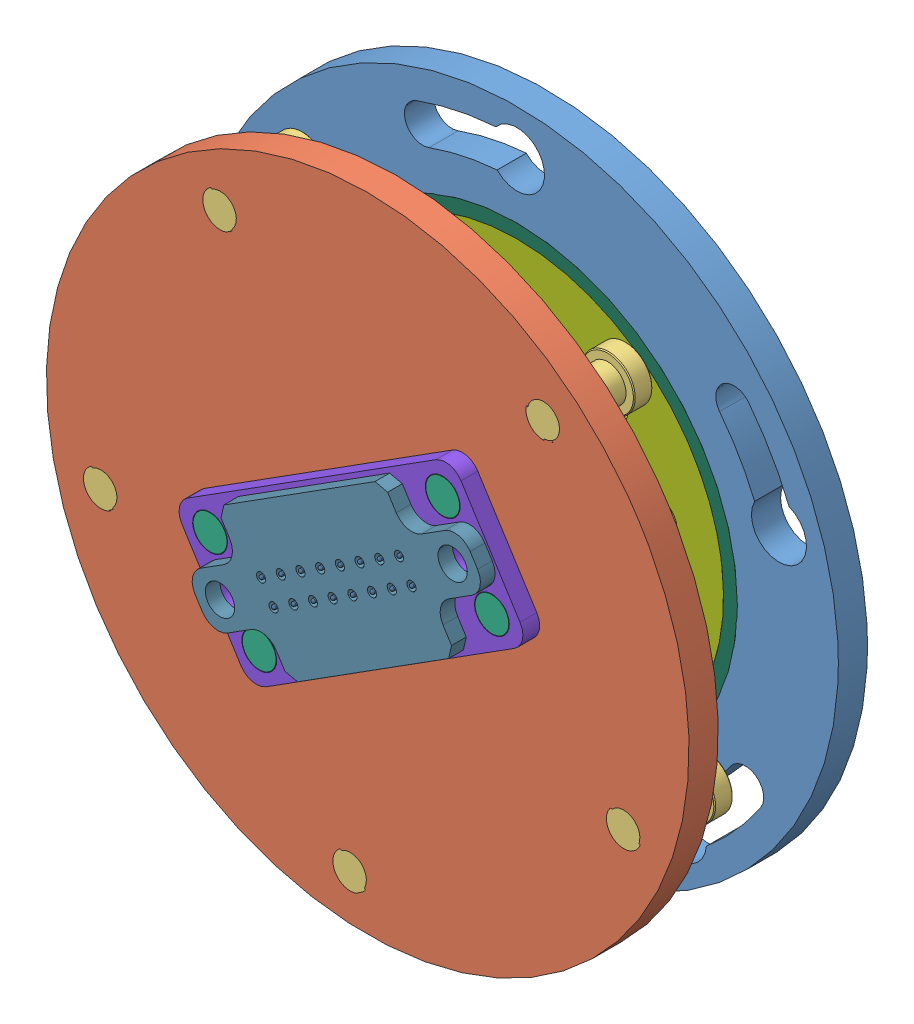
SolidWorks assembly Star_Twist_Lock, configuration Default. Lengths in mm.
Overall size (138 138 26.18).
100 component instances, 15 part files, 39 mates.
Components (placement in the parent):
- Star_Twist_Lock_Female_Plate-1: Star_Twist_Lock_Female_Plate [Default] at (10.9532 52.4325 90.508) size (100 100 3.17)
- Star_Twist_Lock_Male_Plate-1: Star_Twist_Lock_Male_Plate [Default] at (10.9532 52.4325 106.7596) x (0.844579 0.535431 0) z (0 0 1) size (100 100 3.17)
- dowel_shelf_pin-1: dowel_shelf_pin [Default] at (-5.1097 77.7699 109.9346) x (1 0 0) z (0 1 0) size (5.8 9 5.8)
- dowel_shelf_pin-4: dowel_shelf_pin [Default] at (30.0868 75.5389 109.9346) x (1 0 0) z (0 1 0) size (5.8 9 5.8)
- dowel_shelf_pin-5: dowel_shelf_pin [Default] at (38.8414 41.3757 109.9346) x (1 0 0) z (0 1 0) size (5.8 9 5.8)
- dowel_shelf_pin-6: dowel_shelf_pin [Default] at (9.0555 22.4926 109.9346) x (1 0 0) z (0 1 0) size (5.8 9 5.8)
- dowel_shelf_pin-7: dowel_shelf_pin [Default] at (-18.1077 44.9854 109.9346) x (1 0 0) z (0 1 0) size (5.8 9 5.8)
- mill-max-419-10-216-00-001000-1: mill-max-419-10-216-00-001000 [MillMaxsldprt2014419-XX-XXX-00-0010001610uGoldoverNickelPage14off] at (3.9904 45.0109 94.699) x (0.844579 0.535431 0) z (0.535431 -0.844579 0) size (20.32 7.37 5.08)
  - mill-max-419-10-216-00-001000_P4XX-21-010-00-000000-1: mill-max-419-10-216-00-001000_P4XX-21-010-00-000000 [P416-21-010-00-000000] at origin size (20.32 2.79 5.08)
  - mill-max-419-10-216-00-001000_1942-1: mill-max-419-10-216-00-001000_1942 [Default] at (0.9644 0 -1.27) x (0 -1 0) z (0 0 1) size (7.37 1.78 1.78)
  - mill-max-419-10-216-00-001000_1942-35: mill-max-419-10-216-00-001000_1942 [Default] at (0.9644 0 -3.81) x (0 -1 0) z (0 0 1) size (7.37 1.78 1.78)
  - mill-max-419-10-216-00-001000_1942-36: mill-max-419-10-216-00-001000_1942 [Default] at (3.5044 0 -3.81) x (0 -1 0) z (0 0 1) size (7.37 1.78 1.78)
  - mill-max-419-10-216-00-001000_1942-20: mill-max-419-10-216-00-001000_1942 [Default] at (3.5044 0 -1.27) x (0 -1 0) z (0 0 1) size (7.37 1.78 1.78)
  - mill-max-419-10-216-00-001000_1942-37: mill-max-419-10-216-00-001000_1942 [Default] at (6.0444 0 -3.81) x (0 -1 0) z (0 0 1) size (7.37 1.78 1.78)
  - mill-max-419-10-216-00-001000_1942-38: mill-max-419-10-216-00-001000_1942 [Default] at (8.5844 0 -3.81) x (0 -1 0) z (0 0 1) size (7.37 1.78 1.78)
  - mill-max-419-10-216-00-001000_1942-39: mill-max-419-10-216-00-001000_1942 [Default] at (11.1244 0 -3.81) x (0 -1 0) z (0 0 1) size (7.37 1.78 1.78)
  - mill-max-419-10-216-00-001000_1942-40: mill-max-419-10-216-00-001000_1942 [Default] at (13.6644 0 -3.81) x (0 -1 0) z (0 0 1) size (7.37 1.78 1.78)
  - mill-max-419-10-216-00-001000_1942-41: mill-max-419-10-216-00-001000_1942 [Default] at (16.2044 0 -3.81) x (0 -1 0) z (0 0 1) size (7.37 1.78 1.78)
  - mill-max-419-10-216-00-001000_1942-42: mill-max-419-10-216-00-001000_1942 [Default] at (18.7444 0 -3.81) x (0 -1 0) z (0 0 1) size (7.37 1.78 1.78)
  - mill-max-419-10-216-00-001000_1942-29: mill-max-419-10-216-00-001000_1942 [Default] at (6.0444 0 -1.27) x (0 -1 0) z (0 0 1) size (7.37 1.78 1.78)
  - mill-max-419-10-216-00-001000_1942-30: mill-max-419-10-216-00-001000_1942 [Default] at (8.5844 0 -1.27) x (0 -1 0) z (0 0 1) size (7.37 1.78 1.78)
  - mill-max-419-10-216-00-001000_1942-31: mill-max-419-10-216-00-001000_1942 [Default] at (11.1244 0 -1.27) x (0 -1 0) z (0 0 1) size (7.37 1.78 1.78)
  - mill-max-419-10-216-00-001000_1942-32: mill-max-419-10-216-00-001000_1942 [Default] at (13.6644 0 -1.27) x (0 -1 0) z (0 0 1) size (7.37 1.78 1.78)
  - mill-max-419-10-216-00-001000_1942-33: mill-max-419-10-216-00-001000_1942 [Default] at (16.2044 0 -1.27) x (0 -1 0) z (0 0 1) size (7.37 1.78 1.78)
  - mill-max-419-10-216-00-001000_1942-34: mill-max-419-10-216-00-001000_1942 [Default] at (18.7444 0 -1.27) x (0 -1 0) z (0 0 1) size (7.37 1.78 1.78)
- Dowel_Pin_93600A133-11: Dowel_Pin_93600A133 [93600A133] at (0.9617 40.1781 103.1596) x (0 0 1) z (-1 0 0) size (17.2 4 4)
- Pogo_Fixture_Female_Front_Plate-1: Pogo_Fixture_Female_Front_Plate [Default] at (10.9532 52.4325 93.683) x (0.844579 0.535431 0) z (0 0 -1) size (100 100 3.17)
- Pogo_Fixture_Male_Front_Plate-2: Pogo_Fixture_Male_Front_Plate [Default] at (10.9532 52.4325 106.7596) x (0.844579 0.535431 0) z (0 0 1) size (36 16 5)
- Dowel_Pin_93600A133-8: Dowel_Pin_93600A133 [93600A133] at (-4.3926 48.6239 103.1596) x (0 0 1) z (-1 0 0) size (17.2 4 4)
- Dowel_Pin_93600A133-9: Dowel_Pin_93600A133 [93600A133] at (20.9448 64.6869 103.1596) x (0 0 1) z (-1 0 0) size (17.2 4 4)
- Dowel_Pin_93600A133-10: Dowel_Pin_93600A133 [93600A133] at (26.2991 56.2411 103.1596) x (0 0 1) z (-1 0 0) size (17.2 4 4)
- mill-max-823-22-016-10-004101-1: mill-max-823-22-016-10-004101 [Default] at (1.2705 49.3014 108.5592) x (0.844579 0.535431 0) z (-0.535431 0.844579 0) size (20.32 7.75 5.08)
  - mill-max-823-22-016-10-004101_P4XX-28-010-00-090000-1: mill-max-823-22-016-10-004101_P4XX-28-010-00-090000 [Default] at origin size (20.32 2.79 5.08)
  - mill-max-823-22-016-10-004101_0963-0-1: mill-max-823-22-016-10-004101_0963-0 [Default] at (0.9644 -4.953 -1.27) x (0 1 0) z (0 0 1) size (4.04 1.31 1.31)
  - mill-max-823-22-016-10-004101_0953-X-1: mill-max-823-22-016-10-004101_0953-X [Default] at (0.9644 -3.2004 -1.27) x (0 1 0) z (-0.980895 0 0.194537) size (2.69 1.83 1.83)
  - mill-max-823-22-016-10-004101_0918-X-1: mill-max-823-22-016-10-004101_0918-X [Default] at (0.9644 -1.1938 -1.27) x (0 1 0) z (0 0 1) size (3.99 1.25 1.25)
  - mill-max-823-22-016-10-004101_6875-0-00-00-75-XX-43-0C-1: mill-max-823-22-016-10-004101_6875-0-00-00-75-XX-43-0C [Default] at (0.9644 0.6557 -1.27) x (-0.956034 0 -0.293257) z (0 -1 0) size (0.2 0.07 3.45)
  - mill-max-823-22-016-10-004101_0963-0-2: mill-max-823-22-016-10-004101_0963-0 [Default] at (0.9644 -4.953 -3.81) x (0 1 0) z (0 0 1) size (4.04 1.31 1.31)
  - mill-max-823-22-016-10-004101_0953-X-2: mill-max-823-22-016-10-004101_0953-X [Default] at (0.9644 -3.2004 -3.81) x (0 1 0) z (0 0 1) size (2.69 1.83 1.83)
  - mill-max-823-22-016-10-004101_0918-X-2: mill-max-823-22-016-10-004101_0918-X [Default] at (0.9644 -1.1938 -3.81) x (0 1 0) z (0.012366 0 0.999924) size (3.99 1.25 1.25)
  - mill-max-823-22-016-10-004101_6875-0-00-00-75-XX-43-0C-2: mill-max-823-22-016-10-004101_6875-0-00-00-75-XX-43-0C [Default] at (0.9644 -2.5164 -3.81) x (-0.692815 0 0.721116) z (0 1 0) size (0.2 0.07 3.45)
  - mill-max-823-22-016-10-004101_6875-0-00-00-75-XX-43-0C-3: mill-max-823-22-016-10-004101_6875-0-00-00-75-XX-43-0C [Default] at (3.5044 -2.5164 -3.81) x (-0.692815 0 0.721116) z (0 1 0) size (0.2 0.07 3.45)
  - mill-max-823-22-016-10-004101_0918-X-3: mill-max-823-22-016-10-004101_0918-X [Default] at (3.5044 -1.1938 -3.81) x (0 1 0) z (0.012366 0 0.999924) size (3.99 1.25 1.25)
  - mill-max-823-22-016-10-004101_0953-X-3: mill-max-823-22-016-10-004101_0953-X [Default] at (3.5044 -3.2004 -3.81) x (0 1 0) z (0 0 1) size (2.69 1.83 1.83)
  - mill-max-823-22-016-10-004101_0963-0-3: mill-max-823-22-016-10-004101_0963-0 [Default] at (3.5044 -4.953 -3.81) x (0 1 0) z (0 0 1) size (4.04 1.31 1.31)
  - mill-max-823-22-016-10-004101_6875-0-00-00-75-XX-43-0C-4: mill-max-823-22-016-10-004101_6875-0-00-00-75-XX-43-0C [Default] at (3.5044 0.6557 -1.27) x (-0.956034 0 -0.293257) z (0 -1 0) size (0.2 0.07 3.45)
  - mill-max-823-22-016-10-004101_0918-X-4: mill-max-823-22-016-10-004101_0918-X [Default] at (3.5044 -1.1938 -1.27) x (0 1 0) z (0 0 1) size (3.99 1.25 1.25)
  - mill-max-823-22-016-10-004101_0953-X-4: mill-max-823-22-016-10-004101_0953-X [Default] at (3.5044 -3.2004 -1.27) x (0 1 0) z (-0.980895 0 0.194537) size (2.69 1.83 1.83)
  - mill-max-823-22-016-10-004101_0963-0-4: mill-max-823-22-016-10-004101_0963-0 [Default] at (3.5044 -4.953 -1.27) x (0 1 0) z (0 0 1) size (4.04 1.31 1.31)
  - mill-max-823-22-016-10-004101_6875-0-00-00-75-XX-43-0C-5: mill-max-823-22-016-10-004101_6875-0-00-00-75-XX-43-0C [Default] at (6.0444 -2.5164 -3.81) x (-0.692815 0 0.721116) z (0 1 0) size (0.2 0.07 3.45)
  - mill-max-823-22-016-10-004101_6875-0-00-00-75-XX-43-0C-6: mill-max-823-22-016-10-004101_6875-0-00-00-75-XX-43-0C [Default] at (8.5844 -2.5164 -3.81) x (-0.692815 0 0.721116) z (0 1 0) size (0.2 0.07 3.45)
  - mill-max-823-22-016-10-004101_6875-0-00-00-75-XX-43-0C-7: mill-max-823-22-016-10-004101_6875-0-00-00-75-XX-43-0C [Default] at (11.1244 -2.5164 -3.81) x (-0.692815 0 0.721116) z (0 1 0) size (0.2 0.07 3.45)
  - mill-max-823-22-016-10-004101_6875-0-00-00-75-XX-43-0C-8: mill-max-823-22-016-10-004101_6875-0-00-00-75-XX-43-0C [Default] at (13.6644 -2.5164 -3.81) x (-0.692815 0 0.721116) z (0 1 0) size (0.2 0.07 3.45)
  - mill-max-823-22-016-10-004101_6875-0-00-00-75-XX-43-0C-9: mill-max-823-22-016-10-004101_6875-0-00-00-75-XX-43-0C [Default] at (16.2044 -2.5164 -3.81) x (-0.692815 0 0.721116) z (0 1 0) size (0.2 0.07 3.45)
  - mill-max-823-22-016-10-004101_6875-0-00-00-75-XX-43-0C-10: mill-max-823-22-016-10-004101_6875-0-00-00-75-XX-43-0C [Default] at (18.7444 -2.5164 -3.81) x (-0.692815 0 0.721116) z (0 1 0) size (0.2 0.07 3.45)
  - mill-max-823-22-016-10-004101_0918-X-5: mill-max-823-22-016-10-004101_0918-X [Default] at (6.0444 -1.1938 -3.81) x (0 1 0) z (0.012366 0 0.999924) size (3.99 1.25 1.25)
  - mill-max-823-22-016-10-004101_0918-X-6: mill-max-823-22-016-10-004101_0918-X [Default] at (8.5844 -1.1938 -3.81) x (0 1 0) z (0.012366 0 0.999924) size (3.99 1.25 1.25)
  - mill-max-823-22-016-10-004101_0918-X-7: mill-max-823-22-016-10-004101_0918-X [Default] at (11.1244 -1.1938 -3.81) x (0 1 0) z (0.012366 0 0.999924) size (3.99 1.25 1.25)
  - mill-max-823-22-016-10-004101_0918-X-8: mill-max-823-22-016-10-004101_0918-X [Default] at (13.6644 -1.1938 -3.81) x (0 1 0) z (0.012366 0 0.999924) size (3.99 1.25 1.25)
  - mill-max-823-22-016-10-004101_0918-X-9: mill-max-823-22-016-10-004101_0918-X [Default] at (16.2044 -1.1938 -3.81) x (0 1 0) z (0.012366 0 0.999924) size (3.99 1.25 1.25)
  - mill-max-823-22-016-10-004101_0918-X-10: mill-max-823-22-016-10-004101_0918-X [Default] at (18.7444 -1.1938 -3.81) x (0 1 0) z (0.012366 0 0.999924) size (3.99 1.25 1.25)
  - mill-max-823-22-016-10-004101_0953-X-5: mill-max-823-22-016-10-004101_0953-X [Default] at (6.0444 -3.2004 -3.81) x (0 1 0) z (0 0 1) size (2.69 1.83 1.83)
  - mill-max-823-22-016-10-004101_0953-X-6: mill-max-823-22-016-10-004101_0953-X [Default] at (8.5844 -3.2004 -3.81) x (0 1 0) z (0 0 1) size (2.69 1.83 1.83)
  - mill-max-823-22-016-10-004101_0953-X-7: mill-max-823-22-016-10-004101_0953-X [Default] at (11.1244 -3.2004 -3.81) x (0 1 0) z (0 0 1) size (2.69 1.83 1.83)
  - mill-max-823-22-016-10-004101_0953-X-8: mill-max-823-22-016-10-004101_0953-X [Default] at (13.6644 -3.2004 -3.81) x (0 1 0) z (0 0 1) size (2.69 1.83 1.83)
  - mill-max-823-22-016-10-004101_0953-X-9: mill-max-823-22-016-10-004101_0953-X [Default] at (16.2044 -3.2004 -3.81) x (0 1 0) z (0 0 1) size (2.69 1.83 1.83)
  - mill-max-823-22-016-10-004101_0953-X-10: mill-max-823-22-016-10-004101_0953-X [Default] at (18.7444 -3.2004 -3.81) x (0 1 0) z (0 0 1) size (2.69 1.83 1.83)
  - mill-max-823-22-016-10-004101_0963-0-5: mill-max-823-22-016-10-004101_0963-0 [Default] at (6.0444 -4.953 -3.81) x (0 1 0) z (0 0 1) size (4.04 1.31 1.31)
  - mill-max-823-22-016-10-004101_0963-0-6: mill-max-823-22-016-10-004101_0963-0 [Default] at (8.5844 -4.953 -3.81) x (0 1 0) z (0 0 1) size (4.04 1.31 1.31)
  - mill-max-823-22-016-10-004101_0963-0-7: mill-max-823-22-016-10-004101_0963-0 [Default] at (11.1244 -4.953 -3.81) x (0 1 0) z (0 0 1) size (4.04 1.31 1.31)
  - mill-max-823-22-016-10-004101_0963-0-8: mill-max-823-22-016-10-004101_0963-0 [Default] at (13.6644 -4.953 -3.81) x (0 1 0) z (0 0 1) size (4.04 1.31 1.31)
  - mill-max-823-22-016-10-004101_0963-0-9: mill-max-823-22-016-10-004101_0963-0 [Default] at (16.2044 -4.953 -3.81) x (0 1 0) z (0 0 1) size (4.04 1.31 1.31)
  - mill-max-823-22-016-10-004101_0963-0-10: mill-max-823-22-016-10-004101_0963-0 [Default] at (18.7444 -4.953 -3.81) x (0 1 0) z (0 0 1) size (4.04 1.31 1.31)
  - mill-max-823-22-016-10-004101_6875-0-00-00-75-XX-43-0C-11: mill-max-823-22-016-10-004101_6875-0-00-00-75-XX-43-0C [Default] at (6.0444 0.6557 -1.27) x (-0.956034 0 -0.293257) z (0 -1 0) size (0.2 0.07 3.45)
  - mill-max-823-22-016-10-004101_6875-0-00-00-75-XX-43-0C-12: mill-max-823-22-016-10-004101_6875-0-00-00-75-XX-43-0C [Default] at (8.5844 0.6557 -1.27) x (-0.956034 0 -0.293257) z (0 -1 0) size (0.2 0.07 3.45)
  - mill-max-823-22-016-10-004101_6875-0-00-00-75-XX-43-0C-13: mill-max-823-22-016-10-004101_6875-0-00-00-75-XX-43-0C [Default] at (11.1244 0.6557 -1.27) x (-0.956034 0 -0.293257) z (0 -1 0) size (0.2 0.07 3.45)
  - mill-max-823-22-016-10-004101_6875-0-00-00-75-XX-43-0C-14: mill-max-823-22-016-10-004101_6875-0-00-00-75-XX-43-0C [Default] at (13.6644 0.6557 -1.27) x (-0.956034 0 -0.293257) z (0 -1 0) size (0.2 0.07 3.45)
  - mill-max-823-22-016-10-004101_6875-0-00-00-75-XX-43-0C-15: mill-max-823-22-016-10-004101_6875-0-00-00-75-XX-43-0C [Default] at (16.2044 0.6557 -1.27) x (-0.956034 0 -0.293257) z (0 -1 0) size (0.2 0.07 3.45)
  - mill-max-823-22-016-10-004101_6875-0-00-00-75-XX-43-0C-16: mill-max-823-22-016-10-004101_6875-0-00-00-75-XX-43-0C [Default] at (18.7444 0.6557 -1.27) x (-0.956034 0 -0.293257) z (0 -1 0) size (0.2 0.07 3.45)
  - mill-max-823-22-016-10-004101_0918-X-11: mill-max-823-22-016-10-004101_0918-X [Default] at (6.0444 -1.1938 -1.27) x (0 1 0) z (0 0 1) size (3.99 1.25 1.25)
  - mill-max-823-22-016-10-004101_0918-X-12: mill-max-823-22-016-10-004101_0918-X [Default] at (8.5844 -1.1938 -1.27) x (0 1 0) z (0 0 1) size (3.99 1.25 1.25)
  - mill-max-823-22-016-10-004101_0918-X-13: mill-max-823-22-016-10-004101_0918-X [Default] at (11.1244 -1.1938 -1.27) x (0 1 0) z (0 0 1) size (3.99 1.25 1.25)
  - mill-max-823-22-016-10-004101_0918-X-14: mill-max-823-22-016-10-004101_0918-X [Default] at (13.6644 -1.1938 -1.27) x (0 1 0) z (0 0 1) size (3.99 1.25 1.25)
  - mill-max-823-22-016-10-004101_0918-X-15: mill-max-823-22-016-10-004101_0918-X [Default] at (16.2044 -1.1938 -1.27) x (0 1 0) z (0 0 1) size (3.99 1.25 1.25)
  - mill-max-823-22-016-10-004101_0918-X-16: mill-max-823-22-016-10-004101_0918-X [Default] at (18.7444 -1.1938 -1.27) x (0 1 0) z (0 0 1) size (3.99 1.25 1.25)
  - mill-max-823-22-016-10-004101_0953-X-11: mill-max-823-22-016-10-004101_0953-X [Default] at (6.0444 -3.2004 -1.27) x (0 1 0) z (-0.980895 0 0.194537) size (2.69 1.83 1.83)
  - mill-max-823-22-016-10-004101_0953-X-12: mill-max-823-22-016-10-004101_0953-X [Default] at (8.5844 -3.2004 -1.27) x (0 1 0) z (-0.980895 0 0.194537) size (2.69 1.83 1.83)
  - mill-max-823-22-016-10-004101_0953-X-13: mill-max-823-22-016-10-004101_0953-X [Default] at (11.1244 -3.2004 -1.27) x (0 1 0) z (-0.980895 0 0.194537) size (2.69 1.83 1.83)
  - mill-max-823-22-016-10-004101_0953-X-14: mill-max-823-22-016-10-004101_0953-X [Default] at (13.6644 -3.2004 -1.27) x (0 1 0) z (-0.980895 0 0.194537) size (2.69 1.83 1.83)
  - mill-max-823-22-016-10-004101_0953-X-15: mill-max-823-22-016-10-004101_0953-X [Default] at (16.2044 -3.2004 -1.27) x (0 1 0) z (-0.980895 0 0.194537) size (2.69 1.83 1.83)
  - mill-max-823-22-016-10-004101_0953-X-16: mill-max-823-22-016-10-004101_0953-X [Default] at (18.7444 -3.2004 -1.27) x (0 1 0) z (-0.980895 0 0.194537) size (2.69 1.83 1.83)
  - mill-max-823-22-016-10-004101_0963-0-11: mill-max-823-22-016-10-004101_0963-0 [Default] at (6.0444 -4.953 -1.27) x (0 1 0) z (0 0 1) size (4.04 1.31 1.31)
  - mill-max-823-22-016-10-004101_0963-0-12: mill-max-823-22-016-10-004101_0963-0 [Default] at (8.5844 -4.953 -1.27) x (0 1 0) z (0 0 1) size (4.04 1.31 1.31)
  - mill-max-823-22-016-10-004101_0963-0-13: mill-max-823-22-016-10-004101_0963-0 [Default] at (11.1244 -4.953 -1.27) x (0 1 0) z (0 0 1) size (4.04 1.31 1.31)
  - mill-max-823-22-016-10-004101_0963-0-14: mill-max-823-22-016-10-004101_0963-0 [Default] at (13.6644 -4.953 -1.27) x (0 1 0) z (0 0 1) size (4.04 1.31 1.31)
  - mill-max-823-22-016-10-004101_0963-0-15: mill-max-823-22-016-10-004101_0963-0 [Default] at (16.2044 -4.953 -1.27) x (0 1 0) z (0 0 1) size (4.04 1.31 1.31)
  - mill-max-823-22-016-10-004101_0963-0-16: mill-max-823-22-016-10-004101_0963-0 [Default] at (18.7444 -4.953 -1.27) x (0 1 0) z (0 0 1) size (4.04 1.31 1.31)
- 16pin_PCB-1: 16pin_PCB [Default] at (10.9532 52.4325 111.7596) x (0.844579 0.535431 0) z (0 0 1) size (35.48 15 1.6)
- 16pin_PCB-2: 16pin_PCB [Default] at (10.9532 52.4325 88.908) x (0.844579 0.535431 0) z (0 0 1) size (35.48 15 1.6)
- Twist_Lock_Bearing-1: Twist_Lock_Bearing [Default] at (10.9532 52.4325 90.508) size (48 48 3.17)
Mates (geometry in assembly coordinates):
- Concentric1: concentric anti-aligned: cylinder of Star_Twist_Lock_Male_Plate-1 through (-5.1097 77.7699 109.9346) axis (0 0 -1) radius 1.75; cylinder of dowel_shelf_pin-1 through (-5.1097 77.7699 109.9346) axis (0 0 1) radius 2
- Coincident1: coincident aligned: plane of Star_Twist_Lock_Male_Plate-1 through (10.9532 52.4325 109.9346) normal (0 0 1); plane of dowel_shelf_pin-1 through (-3.1097 77.7699 109.9346) normal (0 0 1)
- Coincident2: coincident aligned: plane of Star_Twist_Lock_Male_Plate-1 through (10.9532 52.4325 109.9346) normal (0 0 1); plane of dowel_shelf_pin-4 through (32.0868 75.5389 109.9346) normal (0 0 1)
- Concentric4: concentric anti-aligned: cylinder of Star_Twist_Lock_Male_Plate-1 through (30.0868 75.5389 109.9346) axis (0 0 -1) radius 1.75; cylinder of dowel_shelf_pin-4 through (30.0868 75.5389 109.9346) axis (0 0 1) radius 2
- Concentric5: concentric anti-aligned: cylinder of Star_Twist_Lock_Male_Plate-1 through (38.8414 41.3757 109.9346) axis (0 0 -1) radius 1.75; cylinder of dowel_shelf_pin-5 through (38.8414 41.3757 109.9346) axis (0 0 1) radius 2
- Coincident3: coincident aligned: plane of Star_Twist_Lock_Male_Plate-1 through (10.9532 52.4325 109.9346) normal (0 0 1); plane of dowel_shelf_pin-5 through (40.8414 41.3757 109.9346) normal (0 0 1)
- Concentric6: concentric anti-aligned: cylinder of Star_Twist_Lock_Male_Plate-1 through (9.0555 22.4926 109.9346) axis (0 0 -1) radius 1.75; cylinder of dowel_shelf_pin-6 through (9.0555 22.4926 109.9346) axis (0 0 1) radius 2
- Coincident4: coincident aligned: plane of Star_Twist_Lock_Male_Plate-1 through (10.9532 52.4325 109.9346) normal (0 0 1); plane of dowel_shelf_pin-6 through (11.0555 22.4926 109.9346) normal (0 0 1)
- Concentric7: concentric anti-aligned: cylinder of Star_Twist_Lock_Male_Plate-1 through (-18.1077 44.9854 109.9346) axis (0 0 -1) radius 1.75; cylinder of dowel_shelf_pin-7 through (-18.1077 44.9854 109.9346) axis (0 0 1) radius 2
- Coincident5: coincident aligned: plane of Star_Twist_Lock_Male_Plate-1 through (10.9532 52.4325 109.9346) normal (0 0 1); plane of dowel_shelf_pin-7 through (-16.1077 44.9854 109.9346) normal (0 0 1)
- Concentric8: concentric aligned: cylinder of Star_Twist_Lock_Female_Plate-1 through (10.9532 52.4325 93.683) axis (0 0 -1) radius 35; cylinder of Star_Twist_Lock_Male_Plate-1 through (10.9532 52.4325 109.9346) axis (0 0 -1) radius 35
- Concentric13: concentric anti-aligned: cylinder of Dowel_Pin_93600A133-11 through (0.9617 40.1781 95.1596) axis (0 0 1) radius 2; cylinder of Pogo_Fixture_Male_Front_Plate-2 through (0.9617 40.1781 111.7596) axis (0 0 -1) radius 1.9
- Coincident10: coincident aligned: plane of Dowel_Pin_93600A133-11 through (0.9617 40.1781 111.7596) normal (0 0 1); plane of Pogo_Fixture_Male_Front_Plate-2 through (21.2539 66.0669 111.7596) normal (0 0 1)
- Coincident11: coincident aligned: plane of Pogo_Fixture_Male_Front_Plate-2 through (21.2539 66.0669 111.7596) normal (0 0 1); plane of Dowel_Pin_93600A133-8 through (-4.3926 48.6239 111.7596) normal (0 0 1)
- Concentric14: concentric anti-aligned: cylinder of Pogo_Fixture_Male_Front_Plate-2 through (-4.3926 48.6239 111.7596) axis (0 0 -1) radius 1.9; cylinder of Dowel_Pin_93600A133-8 through (-4.3926 48.6239 95.1596) axis (0 0 1) radius 2
- Concentric15: concentric anti-aligned: cylinder of Pogo_Fixture_Male_Front_Plate-2 through (20.9448 64.6869 111.7596) axis (0 0 -1) radius 1.9; cylinder of Dowel_Pin_93600A133-9 through (20.9448 64.6869 95.1596) axis (0 0 1) radius 2
- Coincident12: coincident aligned: plane of Dowel_Pin_93600A133-8 through (-4.3926 48.6239 111.7596) normal (0 0 1); plane of Dowel_Pin_93600A133-9 through (20.9448 64.6869 111.7596) normal (0 0 1)
- Concentric16: concentric anti-aligned: cylinder of Pogo_Fixture_Male_Front_Plate-2 through (26.2991 56.2411 111.7596) axis (0 0 -1) radius 1.9; cylinder of Dowel_Pin_93600A133-10 through (26.2991 56.2411 95.1596) axis (0 0 1) radius 2
- Coincident13: coincident aligned: plane of Dowel_Pin_93600A133-9 through (20.9448 64.6869 111.7596) normal (0 0 1); plane of Dowel_Pin_93600A133-10 through (26.2991 56.2411 111.7596) normal (0 0 1)
- Coincident14: coincident anti-aligned: plane of mill-max-823-22-016-10-004101-1/mill-max-823-22-016-10-004101_0953-X-2 through (4.411 47.8769 111.7596) normal (0 0 1); plane of 16pin_PCB-1 through (-2.351 49.6222 111.7596) normal (0 0 -1)
- Concentric17: concentric anti-aligned: cylinder of mill-max-823-22-016-10-004101-1/mill-max-823-22-016-10-004101_0963-0-1 through (2.7649 48.7451 111.8358) axis (0 0 1) radius 0.2159; cylinder of 16pin_PCB-1 through (2.7649 48.7451 113.3596) axis (0 0 -1) radius 0.5
- Concentric18: concentric anti-aligned: cylinder of mill-max-823-22-016-10-004101-1/mill-max-823-22-016-10-004101_0963-0-2 through (4.1249 46.5999 111.8358) axis (0 0 1) radius 0.2159; cylinder of 16pin_PCB-1 through (4.1249 46.5999 113.3596) axis (0 0 -1) radius 0.5
- Coincident15: coincident anti-aligned: plane of Pogo_Fixture_Male_Front_Plate-2 through (21.2539 66.0669 111.7596) normal (0 0 1); plane of 16pin_PCB-1 through (-2.351 49.6222 111.7596) normal (0 0 -1)
- Concentric19: concentric aligned: cylinder of Pogo_Fixture_Male_Front_Plate-2 through (23.6219 60.464 111.7596) axis (0 0 -1) radius 1.6; cylinder of 16pin_PCB-1 through (23.6219 60.464 113.3596) axis (0 0 -1) radius 1.6
- Concentric20: concentric aligned: cylinder of Pogo_Fixture_Male_Front_Plate-2 through (-1.7154 44.401 111.7596) axis (0 0 -1) radius 1.6; cylinder of 16pin_PCB-1 through (-1.7154 44.401 113.3596) axis (0 0 -1) radius 1.6
- Coincident16: coincident anti-aligned: plane of mill-max-419-10-216-00-001000-1/mill-max-419-10-216-00-001000_1942-42 through (18.1784 58.5167 90.508) normal (0 0 -1); plane of 16pin_PCB-2 through (-2.351 49.6222 90.508) normal (0 0 1)
- Concentric21: concentric anti-aligned: cylinder of mill-max-419-10-216-00-001000-1/mill-max-419-10-216-00-001000_1942-42 through (17.7816 58.2651 94.699) axis (0 0 1) radius 0.254; cylinder of 16pin_PCB-2 through (17.7816 58.2651 90.508) axis (0 0 -1) radius 0.5
- Concentric22: concentric aligned: cylinder of mill-max-419-10-216-00-001000-1/mill-max-419-10-216-00-001000_1942-34 through (19.1416 56.1199 94.699) axis (0 0 1) radius 0.254; circle of 16pin_PCB-2
- Concentric23: concentric anti-aligned: cylinder of Pogo_Fixture_Female_Front_Plate-1 through (23.6219 60.464 90.508) axis (0 0 1) radius 1.6; cylinder of 16pin_PCB-2 through (23.6219 60.464 90.508) axis (0 0 -1) radius 1.6
- Concentric24: concentric anti-aligned: cylinder of Pogo_Fixture_Female_Front_Plate-1 through (-1.7154 44.401 90.508) axis (0 0 1) radius 1.6; cylinder of 16pin_PCB-2 through (-1.7154 44.401 90.508) axis (0 0 -1) radius 1.6
- Concentric25: concentric aligned: cylinder of Star_Twist_Lock_Female_Plate-1 through (10.9532 52.4325 93.683) axis (0 0 -1) radius 24; cylinder of Twist_Lock_Bearing-1 through (10.9532 52.4325 93.683) axis (0 0 -1) radius 24
- Coincident18: coincident aligned: plane of Star_Twist_Lock_Female_Plate-1 through (10.9532 52.4325 90.508) normal (0 0 -1); plane of Twist_Lock_Bearing-1 through (10.9532 52.4325 90.508) normal (0 0 -1)
- Coincident19: coincident anti-aligned: plane of Pogo_Fixture_Female_Front_Plate-1 through (10.9532 52.4325 90.508) normal (0 0 -1); plane of 16pin_PCB-2 through (-2.351 49.6222 90.508) normal (0 0 1)
- Coincident20: coincident aligned: plane of Star_Twist_Lock_Female_Plate-1 through (10.9532 52.4325 93.683) normal (0 0 1); plane of Pogo_Fixture_Female_Front_Plate-1 through (10.9532 52.4325 93.683) normal (0 0 1)
- Concentric26: concentric anti-aligned: cylinder of Pogo_Fixture_Female_Front_Plate-1 through (10.9532 52.4325 90.508) axis (0 0 1) radius 22.5; cylinder of Twist_Lock_Bearing-1 through (10.9532 52.4325 93.683) axis (0 0 -1) radius 22.5
- Coincident21: coincident aligned: plane of Star_Twist_Lock_Male_Plate-1 through (10.9532 52.4325 106.7596) normal (0 0 -1); plane of Pogo_Fixture_Male_Front_Plate-2 through (21.2539 66.0669 106.7596) normal (0 0 -1)
- Coincident22: coincident anti-aligned: plane of Star_Twist_Lock_Male_Plate-1 through (28.75 54.2428 109.9346) normal (-0.535431 0.844579 0); plane of Pogo_Fixture_Male_Front_Plate-2 through (28.75 54.2428 111.7596) normal (0.535431 -0.844579 0)
- Coincident23: coincident anti-aligned: plane of Star_Twist_Lock_Male_Plate-1 through (29.3683 57.0028 109.9346) normal (-0.844579 -0.535431 0); plane of Pogo_Fixture_Male_Front_Plate-2 through (29.3683 57.0028 111.7596) normal (0.844579 0.535431 0)
- Concentric27: concentric aligned: cylinder of Pogo_Fixture_Female_Front_Plate-1 through (20.9448 64.6869 90.508) axis (0 0 1) radius 2.1; cylinder of Dowel_Pin_93600A133-9 through (20.9448 64.6869 95.1596) axis (0 0 1) radius 2
